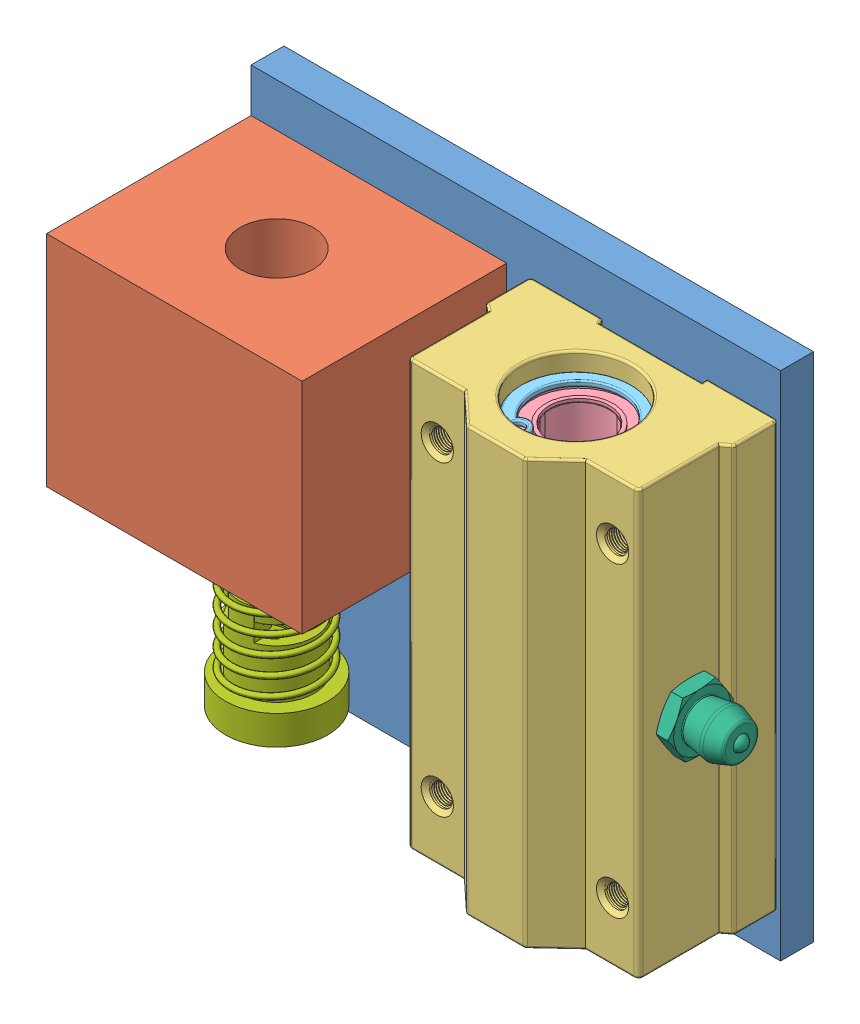
SolidWorks assembly x-axis-right-side, configuration Default. Lengths in mm.
Overall size (79.67 70 32.5).
9 component instances, 7 part files, 8 mates.
Components (placement in the parent):
- x-axis-right-base-1: x-axis-right-base [Default] at origin size (72.5 70 4.5)
- tr8-nut-housing-1: tr8-nut-housing [Default] at (-18.9919 12.6417 0) x (-1 0 0) z (0 0 1) size (35 30 28.09)
- Montagem-assembly-1: Montagem-assembly [Valor predeterminado] at (11.5958 59.7169 11.8237) x (1 0 0) z (0 -1 0) size (41.42 22 58.1)
  - pillow large bore 8mm - Cópia-1: pillow large bore 8mm - Cópia [Valor predeterminado] at (-13.5719 -11.8237 29.05) size (34 22 58.1)
  - rolamento-estampado-1: rolamento-estampado [Valor predeterminado] at (10.9355 -20.1198 29.1307) x (0.182236 0.983255 0) z (0 0 1) size (14.99 14.98 51.99)
  - clamp-1: clamp [Valor predeterminado] at (3.6896 -1.3598 83.8366) size (15.6 14.8 0.82)
  - clamp-2: clamp [Valor predeterminado] at (3.6747 -1.3648 31.5914) size (15.6 14.8 0.82)
  - bico-neb-1: bico-neb [Valor predeterminado] at (21.9053 0.0229 58.1325) x (0 -1 0) z (0 0 1) size (9.01 13.57 8.47)
- TR8_8(P4) Antibacklash Nut w. spring-1: TR8_8(P4) Antibacklash Nut w. spring [Default] at (-22.7261 4.2169 14) x (0.999994 0 0.003507) z (0.003507 0 -0.999994) size (22.43 28.66 22.43)
Mates (geometry in assembly coordinates):
- Concentric1: concentric anti-aligned: cylinder of x-axis-right-base-1 through (-34.7261 24.6169 -4.5) axis (0 0 1) radius 2.25; circle of tr8-nut-housing-1
- Concentric2: concentric anti-aligned: cylinder of x-axis-right-base-1 through (-10.7261 6.6169 -4.5) axis (0 0 1) radius 2.25; circle of tr8-nut-housing-1
- Coincident1: coincident anti-aligned: plane of x-axis-right-base-1 through (0 0 0) normal (0 0 1); plane of tr8-nut-housing-1 through (-18.9919 12.6417 0) normal (0 0 -1)
- Coincident2: coincident anti-aligned: plane of x-axis-right-base-1 through (0 0 0) normal (0 0 1); plane of Montagem-assembly-1/pillow large bore 8mm - Cópia-1 through (-1.9761 -27.4331 0) normal (0 0 -1)
- Concentric3: concentric aligned: cylinder of x-axis-right-base-1 through (27.2739 22.6169 -4.5) axis (0 0 1) radius 2.25; cone of Montagem-assembly-1/pillow large bore 8mm - Cópia-1 through (27.2739 22.6169 0) axis (0 0 1)
- Concentric4: concentric aligned: cylinder of x-axis-right-base-1 through (27.2739 -19.3831 -4.5) axis (0 0 1) radius 2.25; cone of Montagem-assembly-1/pillow large bore 8mm - Cópia-1 through (27.2739 -19.3831 0) axis (0 0 1)
- Concentric5: concentric aligned: cylinder of tr8-nut-housing-1 through (-22.7261 0.6169 14) axis (0 -1 0) radius 11.25; cylinder of TR8_8(P4) Antibacklash Nut w. spring-1 through (-22.7261 4.6169 14) axis (0 -1 0) radius 11
- Coincident3: coincident anti-aligned: plane of tr8-nut-housing-1 through (-27.7261 4.6169 14) normal (0 -1 0); plane of TR8_8(P4) Antibacklash Nut w. spring-1 through (-22.7261 4.6169 14) normal (0 1 0)
